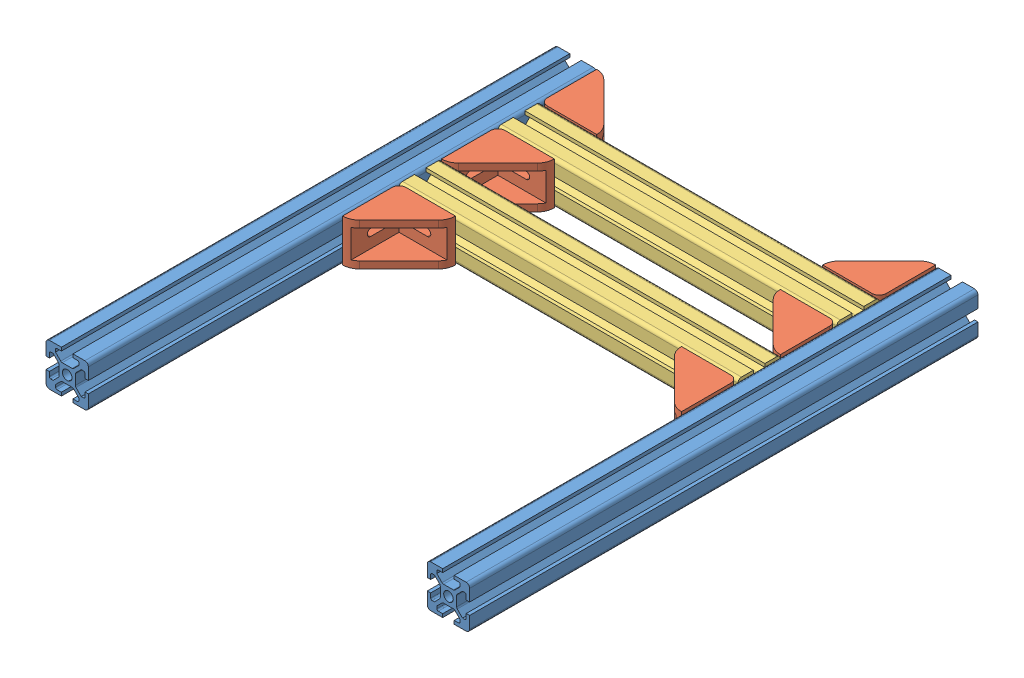
SolidWorks assembly Assem1, configuration Default. Lengths in mm.
Overall size (300 30.85 360).
10 component instances, 3 part files, 32 mates.
Components (placement in the parent):
- 36cmAluminiumSection-1: 36cmAluminiumSection [Default] at (-282.5667 345 -55.4878) x (0 0 -1) z (1 0 0) size (360 30 30)
- 36cmAluminiumSection-2: 36cmAluminiumSection [Default] at (-12.5667 344.1515 -55.4878) x (0 0 -1) z (1 0 0) size (360 30 30)
- CorrnerBlock-1: CorrnerBlock [Default] at (-282.5667 345 -115.4878) x (0 0 -1) z (0 -1 0) size (40 40 30)
- CorrnerBlock-3: CorrnerBlock [Default] at (-42.5667 345 -115.4878) x (-1 0 0) z (0 -1 0) size (40 40 30)
- 24cmAluminiumSection-2: 24cmAluminiumSection [Default] at (-142.5667 345 -85.4878) size (240 30 30)
- CorrnerBlock-4: CorrnerBlock [Default] at (-42.5667 345 -85.4878) x (0 0 1) z (0 -1 0) size (40 40 30)
- CorrnerBlock-6: CorrnerBlock [Default] at (-282.5667 375 -85.4878) x (0 0 1) z (0 1 0) size (40 40 30)
- 24cmAluminiumSection-3: 24cmAluminiumSection [Default] at (-142.5667 345 -15.4878) size (240 30 30)
- CorrnerBlock-7: CorrnerBlock [Default] at (-42.5667 375 -15.4878) x (-1 0 0) z (0 1 0) size (40 40 30)
- CorrnerBlock-8: CorrnerBlock [Default] at (-282.5667 345 -15.4878) x (1 0 0) z (0 -1 0) size (40 40 30)
Mates (geometry in assembly coordinates):
- Parallel1: parallel anti-aligned: plane of 36cmAluminiumSection-1 through (-282.5667 345 -155.4878) normal (1 0 0); plane of 36cmAluminiumSection-2 through (-42.5667 344.1515 -155.4878) normal (-1 0 0)
- Coincident2: coincident aligned: plane of 36cmAluminiumSection-1 through (-282.5667 345 -155.4878) normal (0 0 -1); plane of 36cmAluminiumSection-2 through (-12.5667 344.1515 -155.4878) normal (0 0 -1)
- Distance1: distance = 240 mm anti-aligned: plane of 36cmAluminiumSection-2 through (-42.5667 344.1515 -155.4878) normal (-1 0 0); plane of 36cmAluminiumSection-1 through (-282.5667 345 -155.4878) normal (1 0 0)
- Parallel7: parallel anti-aligned: plane of CorrnerBlock-1 through (-277.5667 342.2867 -115.4878) normal (1 0 0); plane of CorrnerBlock-3 through (-47.5667 372.2867 -155.4878) normal (-1 0 0)
- Coincident17: coincident anti-aligned: line of CorrnerBlock-1 through (-242.5667 372.2867 -115.4878) axis (-1 0 0); line of CorrnerBlock-3 through (-82.5667 372.2867 -115.4878) axis (1 0 0)
- Distance4: distance = 240 mm anti-aligned: plane of CorrnerBlock-1 through (-282.5667 345 -115.4878) normal (-1 0 0); plane of CorrnerBlock-3 through (-42.5667 345 -120.4878) normal (1 0 0)
- Coincident44: coincident aligned: plane of CorrnerBlock-1 through (-282.5667 342.2867 -115.4878) normal (-1 0 0); plane of 24cmAluminiumSection-2 through (-282.5667 369.7867 -87.9878) normal (-1 0 0)
- Coincident45: coincident anti-aligned: plane of CorrnerBlock-1 through (-277.5667 342.2867 -115.4878) normal (0 0 1); plane of 24cmAluminiumSection-2 through (-42.5667 361.3867 -115.4878) normal (0 0 -1)
- Coincident46: coincident aligned: plane of CorrnerBlock-1 through (-277.5667 372.2867 -115.4878) normal (0 1 0); plane of 24cmAluminiumSection-2 through (-42.5667 372.2867 -104.5878) normal (0 1 0)
- Parallel21: parallel anti-aligned: plane of CorrnerBlock-4 through (-47.5667 342.2867 -85.4878) normal (-1 0 0); plane of CorrnerBlock-6 through (-277.5667 372.2867 -85.4878) normal (1 0 0)
- Coincident55: coincident aligned: plane of CorrnerBlock-4 through (-47.5667 342.2867 -85.4878) normal (0 0 -1); plane of CorrnerBlock-6 through (-277.5667 372.2867 -85.4878) normal (0 0 -1)
- Coincident56: coincident aligned: plane of CorrnerBlock-4 through (-47.5667 372.2867 -85.4878) normal (0 1 0); plane of CorrnerBlock-6 through (-277.5667 372.2867 -85.4878) normal (0 1 0)
- Distance12: distance = 240 mm anti-aligned: plane of CorrnerBlock-6 through (-282.5667 375 -85.4878) normal (-1 0 0); plane of CorrnerBlock-4 through (-42.5667 345 -85.4878) normal (1 0 0)
- Coincident58: coincident anti-aligned: plane of 24cmAluminiumSection-2 through (-42.5667 361.3867 -85.4878) normal (0 0 1); plane of CorrnerBlock-6 through (-277.5667 372.2867 -85.4878) normal (0 0 -1)
- Coincident60: coincident aligned: plane of 24cmAluminiumSection-2 through (-282.5667 369.7867 -87.9878) normal (-1 0 0); plane of CorrnerBlock-6 through (-282.5667 372.2867 -85.4878) normal (-1 0 0)
- Coincident61: coincident aligned: plane of 24cmAluminiumSection-2 through (-42.5667 372.2867 -85.4878) normal (0 1 0); plane of CorrnerBlock-6 through (-277.5667 372.2867 -85.4878) normal (0 1 0)
- Coincident63: coincident aligned: line of CorrnerBlock-4 through (-42.5667 342.2867 -45.4878) axis (0 1 0); line of 24cmAluminiumSection-3 through (-42.5667 344.7867 -45.4878) axis (0 1 0)
- Coincident64: coincident aligned: plane of CorrnerBlock-4 through (-42.5667 342.2867 -85.4878) normal (1 0 0); plane of 24cmAluminiumSection-3 through (-42.5667 342.2867 -15.4878) normal (1 0 0)
- Coincident65: coincident aligned: plane of CorrnerBlock-4 through (-47.5667 372.2867 -85.4878) normal (0 1 0); plane of 24cmAluminiumSection-3 through (-42.5667 372.2867 -34.5878) normal (0 1 0)
- Parallel23: parallel anti-aligned: plane of CorrnerBlock-7 through (-47.5667 342.2867 24.5122) normal (-1 0 0); plane of CorrnerBlock-8 through (-277.5667 372.2867 24.5122) normal (1 0 0)
- Coincident75: coincident aligned: plane of CorrnerBlock-7 through (-42.5667 372.2867 -10.4878) normal (0 1 0); plane of CorrnerBlock-8 through (-282.5667 372.2867 -10.4878) normal (0 1 0)
- Parallel26: parallel anti-aligned: plane of CorrnerBlock-7 through (-47.5667 342.2867 24.5122) normal (-1 0 0); plane of CorrnerBlock-8 through (-277.5667 372.2867 24.5122) normal (1 0 0)
- Distance15: distance = 240 mm anti-aligned: plane of CorrnerBlock-8 through (-282.5667 345 -10.4878) normal (-1 0 0); plane of CorrnerBlock-7 through (-42.5667 375 -10.4878) normal (1 0 0)
- Coincident95: coincident aligned: plane of CorrnerBlock-7 through (-42.5667 372.2867 -10.4878) normal (0 1 0); plane of CorrnerBlock-8 through (-282.5667 372.2867 -10.4878) normal (0 1 0)
- Coincident96: coincident aligned: plane of CorrnerBlock-7 through (-42.5667 372.2867 -15.4878) normal (0 0 -1); plane of CorrnerBlock-8 through (-282.5667 342.2867 -15.4878) normal (0 0 -1)
- Coincident97: coincident anti-aligned: plane of 24cmAluminiumSection-3 through (-42.5667 361.3867 -15.4878) normal (0 0 1); plane of CorrnerBlock-8 through (-282.5667 342.2867 -15.4878) normal (0 0 -1)
- Coincident98: coincident aligned: plane of 24cmAluminiumSection-3 through (-42.5667 372.2867 -15.4878) normal (0 1 0); plane of CorrnerBlock-8 through (-282.5667 372.2867 -10.4878) normal (0 1 0)
- Coincident99: coincident aligned: plane of CorrnerBlock-7 through (-42.5667 372.2867 -10.4878) normal (0 1 0); plane of CorrnerBlock-8 through (-282.5667 372.2867 -10.4878) normal (0 1 0)
- Coincident100: coincident aligned: plane of 24cmAluminiumSection-3 through (-282.5667 369.7867 -17.9878) normal (-1 0 0); plane of CorrnerBlock-8 through (-282.5667 342.2867 -10.4878) normal (-1 0 0)
- Coincident101: coincident anti-aligned: plane of 36cmAluminiumSection-1 through (-282.5667 364.1 -155.4878) normal (1 0 0); plane of CorrnerBlock-1 through (-282.5667 345 -115.4878) normal (-1 0 0)
- Coincident102: coincident: plane of 36cmAluminiumSection-1 through (-282.5667 345 -155.4878) normal (0 0 -1); line of CorrnerBlock-1 through (-282.5373 375 -155.4878) axis (0 -1 0)
- Coincident103: coincident aligned: plane of 36cmAluminiumSection-1 through (-282.5667 375 -155.4878) normal (0 1 0); plane of CorrnerBlock-1 through (-277.5667 375 -115.4878) normal (0 1 0)
